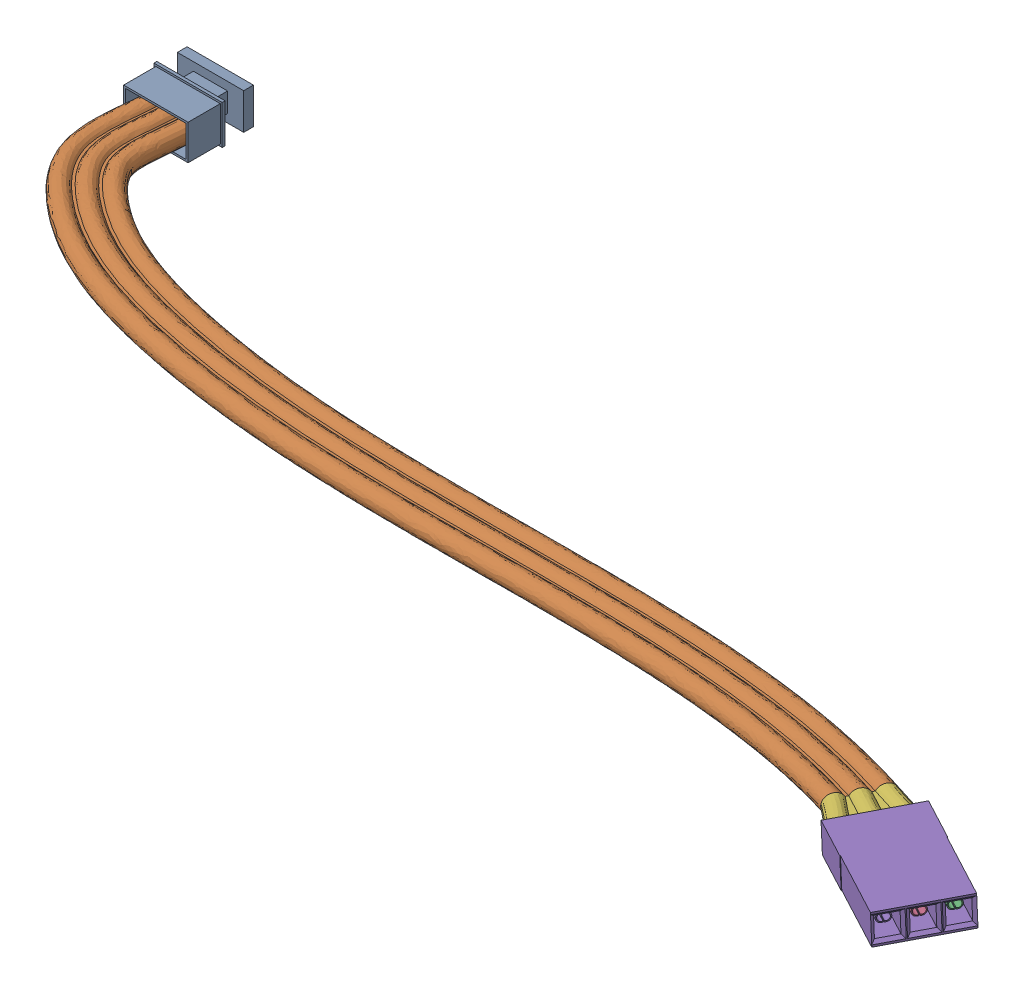
SolidWorks assembly filo completo 3, configuration Default. Lengths in mm.
Overall size (117.35 5.35 43.22).
4 component instances, 4 part files, 10 mates.
Components (placement in the parent):
- Connettore servom-3: Connettore servom [Default] at (4.831 6.0071 -0.15) x (0 -1 0) z (0 0 -1) size (4 7 6.6)
- filo3-1: filo3 [Default] at (1.331 4.0071 -0.15) size (101.7 4.31 30.71)
- Connettore fili-1: Connettore fili [Default] at (109.5648 7.0802 34.2622) x (0.48716 0.019978 -0.873084) z (0.052658 -0.998591 0.006532) size (8.1 13 3)
- terminale fili-1: terminale fili [Default] at (99.9431 6.0646 33.1082) x (0.48716 0.019978 -0.873084) z (-0.871724 -0.049157 -0.487525) size (7.41 2.02 5.7)
Mates (geometry in assembly coordinates):
- Coincidente22: coincident anti-aligned: plane of Connettore fili-1 through (111.3809 4.7064 39.4591) normal (0.48716 0.019978 -0.873084); plane of terminale fili-1 through (101.4251 6.1481 33.937) normal (-0.48716 -0.019978 0.873084)
- Coincidente23: coincident anti-aligned: plane of Connettore fili-1 through (111.3809 4.7064 39.4591) normal (0.48716 0.019978 -0.873084); plane of terminale fili-1 through (101.4251 6.1481 33.937) normal (-0.48716 -0.019978 0.873084)
- Coincidente24: coincident aligned: line of Connettore fili-1 through (99.9431 6.0646 33.1082) axis (0.48716 0.019978 -0.873084); line of terminale fili-1 through (99.9431 6.0646 33.1082) axis (0.48716 0.019978 -0.873084)
- Coincidente26: coincident aligned: line of Connettore fili-1 through (101.0228 4.1073 31.3751) axis (-0.48716 -0.019978 0.873084); line of terminale fili-1 through (100.5352 4.0873 32.2489) axis (-0.48716 -0.019978 0.873084)
- Coincidente43: coincident: point of filo3-1
- Coincidente44: coincident anti-aligned: plane of Connettore servom-3 through (4.831 6.0071 -0.15) normal (0 0 1); plane of filo3-1 through (1.331 4.0071 -0.15) normal (0 0 -1)
- Coincidente45: coincident: circle of filo2-1
- Coincidente46: coincident anti-aligned: plane of terminale fili-1 through (98.3114 4.9433 27.9342) normal (-0.871724 -0.049157 -0.487525); plane of filo3-1 through (98.3114 4.9433 27.9342) normal (0.871724 0.049157 0.487525)
- Coincidente47: coincident: unknown of filo3-1; unknown of terminale fili-1
- Coincidente48: coincident: unknown of filo3-1; unknown of terminale fili-1
